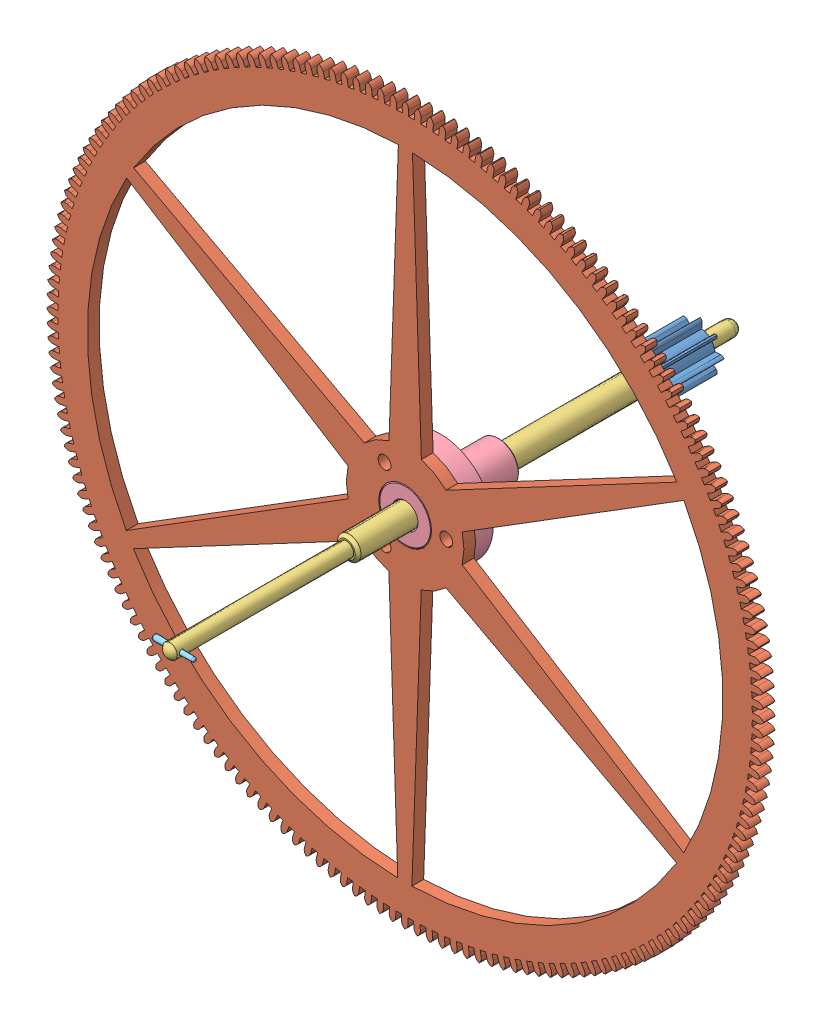
SolidWorks assembly center wheel assy, configuration Default. Lengths in mm.
Overall size (127.02 127.02 96.9).
5 component instances, 5 part files, 8 mates.
Components (placement in the parent):
- great pinion-1: great pinion [Default] at (0 0 -50.2) size (8.11 8.11 10)
- center wheel-1: center wheel [Default] at (0 0 -10) x (1 -0.000968 0) z (0 0 1) size (126.9 126.9 2)
- center arbor-1: center arbor [Default] at origin size (4 4 96.9)
- center collet-1: center collet [Default] at (0 0 -10) size (18 18 16)
- motionwork taper pin-1: motionwork taper pin [Default] at (0 0 29.2) size (7 0.99 0.99)
Mates (geometry in assembly coordinates):
- Concentric14: concentric: cylinder of great pinion-1 through (0 0 -60.2) axis (0 0 1) radius 1.5; cylinder of center arbor-1 through (0 0 29.2339) axis (0 0 1) radius 1.5
- Distance2: distance = 0.3 mm: plane of center arbor-1 through (0 -1.25 -60.5) normal (0 0 -1); plane of great pinion-1 through (-0.33 3.4844 -60.2) normal (0 0 -1)
- Concentric13: concentric: circle of center wheel-1; cylinder of center collet-1 through (0 0 -12) axis (0 0 1) radius 4.5
- Coincident11: coincident: plane of center wheel-1 through (0 0 -10) normal (0 0 1); plane of center collet-1 through (0 0 -10) normal (0 0 1)
- Concentric12: concentric: cylinder of center arbor-1 through (0 0 29.2339) axis (0 0 1) radius 2; cylinder of center collet-1 through (0 0 -26) axis (0 0 1) radius 2
- Distance1: distance = 10 mm: plane of center collet-1 through (0 0 -10) normal (0 0 1); plane of center arbor-1 through (0 -2 0) normal (0 0 1)
- Coincident12: coincident: plane of center arbor-1 through (0 0 0) normal (1 0 0); plane of motionwork taper pin-1 through (0 0 29.2) normal (1 0 0)
- Concentric15: concentric: cylinder of center arbor-1 through (-2 0 29.2) axis (1 0 0) radius 0.45; circle of motionwork taper pin-1
